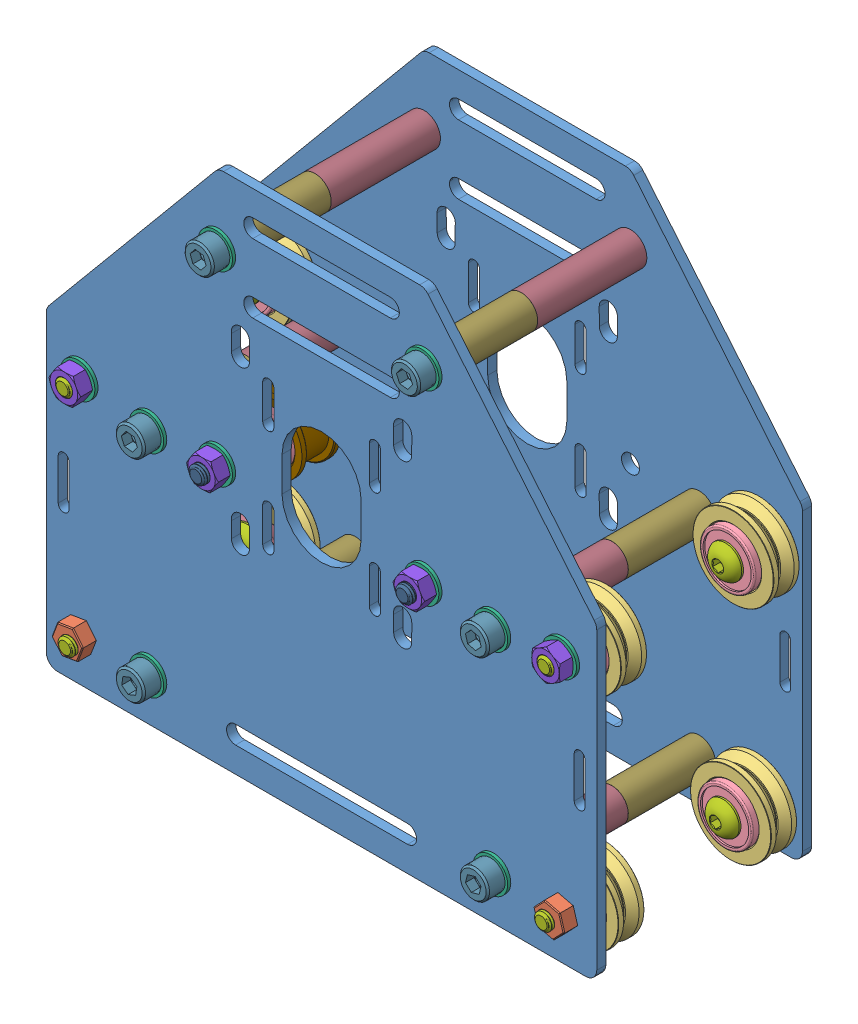
SolidWorks assembly ASM_S2_Yaxis_Plates, configuration Default. Lengths in mm.
Overall size (165.72 150 75.7).
154 component instances, 15 part files, 77 mates.
Components (placement in the parent):
- plate_assembly_stacked-2: plate_assembly_stacked [Default] at (181.8768 0 62.4637) x (-1 0 0) z (0 0 -1) size (164.61 150 32.91)
  - 26029-01-1: 26029-01 [Default] at origin size (160 150 2.66)
  - B18033-1: B18033 [Default] at (160.9384 20.9044 -3.9878) x (-0.352192 0.935928 0) z (0 0 1) size (9.18 7.95 5.26)
  - B18033-2: B18033 [Default] at (20.9384 20.9044 -3.9878) x (-0.283832 -0.958874 0) z (0 0 1) size (9.18 7.95 5.26)
  - 25203-02-1: 25203-02 [Default] at (20.9384 85.5044 9.0568) x (0.995036 -0.099517 0) z (-0.099517 -0.995036 0) size (23.5 11 23.5)
    - 25202-01-1: 25202-01 [Default] at origin size (23.5 7.5 23.5)
    - 25196-01-1: 25196-01 [Default] at (0 -3 0) x (0.224141 0 -0.974557) z (-0.974557 0 -0.224141) size (16 5 16)
    - 25201-01-1: 25201-01 [Default] at (0 -0.5 0) x (0.992075 0 -0.125646) z (0.125646 0 0.992075) size (10 1 10)
    - 25196-01-2: 25196-01 [Default] at (0 3 0) x (-0.996407 0 -0.084695) z (-0.084695 0 0.996407) size (16 5 16)
  - 25287-02-1: 25287-02 [Default] at (20.9384 85.5044 3.5568) size (10 10 0.9)
  - 91239A233-1: 91239A233 [Default] at (20.9384 85.5044 -5.4432) x (1 0 0) z (0 0 -1) size (9.5 9.5 22.91)
  - 25287-02-2: 25287-02 [Default] at (160.2015 20.6271 2.6568) x (-0.923728 -0.383049 0) z (0 0 -1) size (10 10 0.9)
  - 25284-02-1: 25284-02 [Default] at (20.9384 85.5044 -2.9) x (1 0 0) z (0 -1 0) size (8 4.29 9.24)
  - 25287-02-3: 25287-02 [Default] at (160.9384 85.5044 0) size (10 10 0.9)
  - 25287-02-4: 25287-02 [Default] at (160.9384 85.5044 3.5568) size (10 10 0.9)
  - 25287-02-5: 25287-02 [Default] at (21.6934 20.6809 2.6568) x (-0.923728 -0.383049 0) z (0 0 -1) size (10 10 0.9)
  - 25287-02-6: 25287-02 [Default] at (20.9384 85.5044 -0.9) x (1 0 0) z (0 0 -1) size (10 10 0.9)
  - 91239A233-2: 91239A233 [Default] at (21.6934 20.6809 -5.4432) x (1 0 0) z (0 0 -1) size (9.5 9.5 22.91)
  - 25203-02-2: 25203-02 [Default] at (21.6934 20.6809 9.0568) x (1 0 0) z (0 1 0) size (23.5 11 23.5)
    - 25202-01-1: 25202-01 [Default] at origin size (23.5 7.5 23.5)
    - 25196-01-1: 25196-01 [Default] at (0 -3 0) x (0.224141 0 -0.974557) z (-0.974557 0 -0.224141) size (16 5 16)
    - 25201-01-1: 25201-01 [Default] at (0 -0.5 0) x (0.992075 0 -0.125646) z (0.125646 0 0.992075) size (10 1 10)
    - 25196-01-2: 25196-01 [Default] at (0 3 0) x (-0.996407 0 -0.084695) z (-0.084695 0 0.996407) size (16 5 16)
  - 91239A233-3: 91239A233 [Default] at (160.2015 20.6271 -5.4432) x (1 0 0) z (0 0 -1) size (9.5 9.5 22.91)
  - 25203-02-3: 25203-02 [Default] at (160.2015 20.6271 9.0568) x (1 0 0) z (0 1 0) size (23.5 11 23.5)
    - 25202-01-1: 25202-01 [Default] at origin size (23.5 7.5 23.5)
    - 25196-01-1: 25196-01 [Default] at (0 -3 0) x (0.224141 0 -0.974557) z (-0.974557 0 -0.224141) size (16 5 16)
    - 25201-01-1: 25201-01 [Default] at (0 -0.5 0) x (0.992075 0 -0.125646) z (0.125646 0 0.992075) size (10 1 10)
    - 25196-01-2: 25196-01 [Default] at (0 3 0) x (-0.996407 0 -0.084695) z (-0.084695 0 0.996407) size (16 5 16)
  - 91239A233-4: 91239A233 [Default] at (160.9384 85.5044 -5.4432) x (1 0 0) z (0 0 -1) size (9.5 9.5 22.91)
  - 25203-02-4: 25203-02 [Default] at (160.9384 85.5044 9.0568) x (1 0 0) z (0 -1 0) size (23.5 11 23.5)
    - 25202-01-1: 25202-01 [Default] at origin size (23.5 7.5 23.5)
    - 25196-01-1: 25196-01 [Default] at (0 -3 0) x (0.224141 0 -0.974557) z (-0.974557 0 -0.224141) size (16 5 16)
    - 25201-01-1: 25201-01 [Default] at (0 -0.5 0) x (0.992075 0 -0.125646) z (0.125646 0 0.992075) size (10 1 10)
    - 25196-01-2: 25196-01 [Default] at (0 3 0) x (-0.996407 0 -0.084695) z (-0.084695 0 0.996407) size (16 5 16)
  - 25284-02-2: 25284-02 [Default] at (160.9384 85.5044 -2.9) x (0.037474 -0.999298 0) z (-0.999298 -0.037474 0) size (8 4.29 9.24)
  - 25197-02-1: 25197-02 [Default] at (128.9783 132.3034 54.0684) x (0 0 -1) z (-0.954972 -0.296697 0) size (12.6 21 21)
    - 25201-01-1: 25201-01 [Default] at (36.6716 43.7387 22.0081) x (0 1 0) z (0 0 1) size (10 1 10)
    - 25196-01-1: 25196-01 [Default] at (39.1716 43.7387 22.0081) x (0 1 0) z (0 0 1) size (16 5 16)
    - 25196-01-2: 25196-01 [Default] at (33.1716 43.7387 22.0081) x (0 1 0) z (0 0 1) size (16 5 16)
    - 25197-01-1: 25197-01 [Default] at (34.6716 43.7387 22.0081) size (11.2 21 21)
  - 25197-02-2: 25197-02 [Default] at (57.254 35.1797 54.0684) x (0 0 -1) z (0.92458 0.380987 0) size (12.6 21 21)
    - 25201-01-1: 25201-01 [Default] at (36.6716 43.7387 22.0081) x (0 1 0) z (0 0 1) size (10 1 10)
    - 25196-01-1: 25196-01 [Default] at (39.1716 43.7387 22.0081) x (0 1 0) z (0 0 1) size (16 5 16)
    - 25196-01-2: 25196-01 [Default] at (33.1716 43.7387 22.0081) x (0 1 0) z (0 0 1) size (16 5 16)
    - 25197-01-1: 25197-01 [Default] at (34.6716 43.7387 22.0081) size (11.2 21 21)
  - 25286-05-1: 25286-05 [Default] at (120.9384 84.0044 -6.6032) x (-0.651947 -0.758265 0) z (0 0 -1) size (9.5 9.5 32.91)
  - 25287-02-7: 25287-02 [Default] at (120.9384 84.0044 0) size (10 10 0.9)
  - 25284-02-3: 25284-02 [Default] at (120.9384 84.0044 -2.9) x (0.037474 -0.999298 0) z (-0.999298 -0.037474 0) size (8 4.29 9.24)
  - 25286-05-2: 25286-05 [Default] at (60.9384 84.0044 -6.6032) x (0.940642 0.3394 0) z (0 0 -1) size (9.5 9.5 32.91)
  - 25284-02-4: 25284-02 [Default] at (60.9384 84.0044 -2.9) x (-0.037474 0.999298 0) z (-0.999298 -0.037474 0) size (8 4.29 9.24)
  - 25287-02-8: 25287-02 [Default] at (60.9384 84.0044 0) x (-0.99589 0.090569 0) z (0 0 1) size (10 10 0.9)
  - 25312-14-1: 25312-14 [Default] at (60.9384 84.0044 4.4568) x (-0.162265 0.986747 0) z (0 0 1) size (9.53 9.53 7.94)
  - 25312-14-2: 25312-14 [Default] at (120.9384 84.0044 12.3968) x (0.519042 -0.854749 0) z (0 0 -1) size (9.53 9.53 7.94)
  - 25287-02-9: 25287-02 [Default] at (60.9384 84.0044 2.6568) x (0.999419 -0.034095 0) z (0 0 -1) size (10 10 0.9)
  - 25287-02-10: 25287-02 [Default] at (60.9384 84.0044 4.4568) x (0.999419 0.034095 0) z (0 0 1) size (10 10 0.9)
  - 25287-02-11: 25287-02 [Default] at (120.9384 84.0044 3.5568) x (0.999419 -0.034095 0) z (0 0 -1) size (10 10 0.9)
  - 25287-02-12: 25287-02 [Default] at (120.9384 84.0044 2.6568) x (0.999419 -0.034095 0) z (0 0 -1) size (10 10 0.9)
- plate_assembly_stacked-1: plate_assembly_stacked [No_Belt] at origin size (164.61 150 22.91)
  - 26029-01-1: 26029-01 [Default] at origin size (160 150 2.66)
  - B18033-1: B18033 [Default] at (160.9384 20.9044 -3.9878) x (-0.352192 0.935928 0) z (0 0 1) size (9.18 7.95 5.26)
  - B18033-2: B18033 [Default] at (20.9384 20.9044 -3.9878) x (-0.283832 -0.958874 0) z (0 0 1) size (9.18 7.95 5.26)
  - 25203-02-1: 25203-02 [Default] at (20.9384 85.5044 9.0568) x (0.995036 -0.099517 0) z (-0.099517 -0.995036 0) size (23.5 11 23.5)
    - 25202-01-1: 25202-01 [Default] at origin size (23.5 7.5 23.5)
    - 25196-01-1: 25196-01 [Default] at (0 -3 0) x (0.224141 0 -0.974557) z (-0.974557 0 -0.224141) size (16 5 16)
    - 25201-01-1: 25201-01 [Default] at (0 -0.5 0) x (0.992075 0 -0.125646) z (0.125646 0 0.992075) size (10 1 10)
    - 25196-01-2: 25196-01 [Default] at (0 3 0) x (-0.996407 0 -0.084695) z (-0.084695 0 0.996407) size (16 5 16)
  - 25287-02-1: 25287-02 [Default] at (20.9384 85.5044 3.5568) size (10 10 0.9)
  - 91239A233-1: 91239A233 [Default] at (20.9384 85.5044 -5.4432) x (1 0 0) z (0 0 -1) size (9.5 9.5 22.91)
  - 25287-02-2: 25287-02 [Default] at (160.2015 20.6271 2.6568) x (-0.923728 -0.383049 0) z (0 0 -1) size (10 10 0.9)
  - 25284-02-1: 25284-02 [Default] at (20.9384 85.5044 -2.9) x (1 0 0) z (0 -1 0) size (8 4.29 9.24)
  - 25287-02-3: 25287-02 [Default] at (160.9384 85.5044 0) size (10 10 0.9)
  - 25287-02-4: 25287-02 [Default] at (160.9384 85.5044 3.5568) size (10 10 0.9)
  - 25287-02-5: 25287-02 [Default] at (21.6934 20.6809 2.6568) x (-0.923728 -0.383049 0) z (0 0 -1) size (10 10 0.9)
  - 25287-02-6: 25287-02 [Default] at (20.9384 85.5044 -0.9) x (1 0 0) z (0 0 -1) size (10 10 0.9)
  - 91239A233-2: 91239A233 [Default] at (21.6934 20.6809 -5.4432) x (1 0 0) z (0 0 -1) size (9.5 9.5 22.91)
  - 25203-02-2: 25203-02 [Default] at (21.6934 20.6809 9.0568) x (1 0 0) z (0 1 0) size (23.5 11 23.5)
    - 25202-01-1: 25202-01 [Default] at origin size (23.5 7.5 23.5)
    - 25196-01-1: 25196-01 [Default] at (0 -3 0) x (0.224141 0 -0.974557) z (-0.974557 0 -0.224141) size (16 5 16)
    - 25201-01-1: 25201-01 [Default] at (0 -0.5 0) x (0.992075 0 -0.125646) z (0.125646 0 0.992075) size (10 1 10)
    - 25196-01-2: 25196-01 [Default] at (0 3 0) x (-0.996407 0 -0.084695) z (-0.084695 0 0.996407) size (16 5 16)
  - 91239A233-3: 91239A233 [Default] at (160.2015 20.6271 -5.4432) x (1 0 0) z (0 0 -1) size (9.5 9.5 22.91)
  - 25203-02-3: 25203-02 [Default] at (160.2015 20.6271 9.0568) x (1 0 0) z (0 1 0) size (23.5 11 23.5)
    - 25202-01-1: 25202-01 [Default] at origin size (23.5 7.5 23.5)
    - 25196-01-1: 25196-01 [Default] at (0 -3 0) x (0.224141 0 -0.974557) z (-0.974557 0 -0.224141) size (16 5 16)
    - 25201-01-1: 25201-01 [Default] at (0 -0.5 0) x (0.992075 0 -0.125646) z (0.125646 0 0.992075) size (10 1 10)
    - 25196-01-2: 25196-01 [Default] at (0 3 0) x (-0.996407 0 -0.084695) z (-0.084695 0 0.996407) size (16 5 16)
  - 91239A233-4: 91239A233 [Default] at (160.9384 85.5044 -5.4432) x (1 0 0) z (0 0 -1) size (9.5 9.5 22.91)
  - 25203-02-4: 25203-02 [Default] at (160.9384 85.5044 9.0568) x (1 0 0) z (0 -1 0) size (23.5 11 23.5)
    - 25202-01-1: 25202-01 [Default] at origin size (23.5 7.5 23.5)
    - 25196-01-1: 25196-01 [Default] at (0 -3 0) x (0.224141 0 -0.974557) z (-0.974557 0 -0.224141) size (16 5 16)
    - 25201-01-1: 25201-01 [Default] at (0 -0.5 0) x (0.992075 0 -0.125646) z (0.125646 0 0.992075) size (10 1 10)
    - 25196-01-2: 25196-01 [Default] at (0 3 0) x (-0.996407 0 -0.084695) z (-0.084695 0 0.996407) size (16 5 16)
  - 25284-02-2: 25284-02 [Default] at (160.9384 85.5044 -2.9) x (0.037474 -0.999298 0) z (-0.999298 -0.037474 0) size (8 4.29 9.24)
  - 25197-02-1: 25197-02 [Default] at (128.9783 132.3034 54.0684) x (0 0 -1) z (-0.954972 -0.296697 0) size (12.6 21 21) (suppressed, hidden)
    - 25201-01-1: 25201-01 [Default] at (36.6716 43.7387 22.0081) x (0 1 0) z (0 0 1) size (10 1 10)
    - 25196-01-1: 25196-01 [Default] at (39.1716 43.7387 22.0081) x (0 1 0) z (0 0 1) size (16 5 16)
    - 25196-01-2: 25196-01 [Default] at (33.1716 43.7387 22.0081) x (0 1 0) z (0 0 1) size (16 5 16)
    - 25197-01-1: 25197-01 [Default] at (34.6716 43.7387 22.0081) size (11.2 21 21)
  - 25197-02-2: 25197-02 [Default] at (57.254 35.1797 54.0684) x (0 0 -1) z (0.92458 0.380987 0) size (12.6 21 21) (suppressed, hidden)
    - 25201-01-1: 25201-01 [Default] at (36.6716 43.7387 22.0081) x (0 1 0) z (0 0 1) size (10 1 10)
    - 25196-01-1: 25196-01 [Default] at (39.1716 43.7387 22.0081) x (0 1 0) z (0 0 1) size (16 5 16)
    - 25196-01-2: 25196-01 [Default] at (33.1716 43.7387 22.0081) x (0 1 0) z (0 0 1) size (16 5 16)
    - 25197-01-1: 25197-01 [Default] at (34.6716 43.7387 22.0081) size (11.2 21 21)
  - 25286-05-1: 25286-05 [Default] at (120.9384 84.0044 -6.6032) x (-0.651947 -0.758265 0) z (0 0 -1) size (9.5 9.5 32.91) (suppressed, hidden)
  - 25287-02-7: 25287-02 [Default] at (120.9384 84.0044 0) size (10 10 0.9) (suppressed, hidden)
  - 25284-02-3: 25284-02 [Default] at (120.9384 84.0044 -2.9) x (0.037474 -0.999298 0) z (-0.999298 -0.037474 0) size (8 4.29 9.24) (suppressed, hidden)
  - 25286-05-2: 25286-05 [Default] at (60.9384 84.0044 -6.6032) x (0.940642 0.3394 0) z (0 0 -1) size (9.5 9.5 32.91) (suppressed, hidden)
  - 25284-02-4: 25284-02 [Default] at (60.9384 84.0044 -2.9) x (-0.037474 0.999298 0) z (-0.999298 -0.037474 0) size (8 4.29 9.24) (suppressed, hidden)
  - 25287-02-8: 25287-02 [Default] at (60.9384 84.0044 0) x (-0.99589 0.090569 0) z (0 0 1) size (10 10 0.9) (suppressed, hidden)
  - 25312-14-1: 25312-14 [Default] at (60.9384 84.0044 4.4568) x (-0.162265 0.986747 0) z (0 0 1) size (9.53 9.53 7.94) (suppressed, hidden)
  - 25312-14-2: 25312-14 [Default] at (120.9384 84.0044 12.3968) x (0.519042 -0.854749 0) z (0 0 -1) size (9.53 9.53 7.94) (suppressed, hidden)
  - 25287-02-9: 25287-02 [Default] at (60.9384 84.0044 2.6568) x (0.999419 -0.034095 0) z (0 0 -1) size (10 10 0.9) (suppressed, hidden)
  - 25287-02-10: 25287-02 [Default] at (60.9384 84.0044 4.4568) x (0.999419 0.034095 0) z (0 0 1) size (10 10 0.9) (suppressed, hidden)
  - 25287-02-11: 25287-02 [Default] at (120.9384 84.0044 3.5568) x (0.999419 -0.034095 0) z (0 0 -1) size (10 10 0.9) (suppressed, hidden)
  - 25287-02-12: 25287-02 [Default] at (120.9384 84.0044 2.6568) x (0.999419 -0.034095 0) z (0 0 -1) size (10 10 0.9) (suppressed, hidden)
- AS38-12-64-1: AS38-12-64 [Default] at (120.9384 138.2044 59.8068) x (1 0 0) z (0 0 -1) size (9.53 9.53 25.4)
- 91290A272-1: 91290A272 [Default] at (152.9795 421.0336 165.2742) x (-0.956811 0.027475 0.289409) z (-0.289409 0.004064 -0.957197) (suppressed, hidden)
- 25284-02-7: 25284-02 [Default] at (120.9384 138.2044 -2.9) x (-0.5 0.866025 0) z (0.866025 0.5 0) size (8 4.29 9.24)
- 25287-02-18: 25287-02 [Default] at (120.9384 138.2044 63.3637) x (0.999606 -0.028076 0) z (0 0 1) size (10 10 0.9)
- 25287-02-19: 25287-02 [Default] at (120.9384 138.2044 -0.9) x (-0.999993 0.003617 0) z (0 0 -1) size (10 10 0.9)
- AS38-12-80-1: AS38-12-80 [Default] at (120.9384 138.2044 2.6568) x (-0.089218 0.996012 0) z (0 0 1) size (9.53 9.53 31.75)
- 25284-02-10: 25284-02 [Default] at (140.9384 82.4044 -2.9) x (0.999993 -0.003617 0) z (-0.003617 -0.999993 0) size (8 4.29 9.24)
- 25287-02-25: 25287-02 [Default] at (140.9384 82.4044 -0.9) x (-0.301994 -0.95331 0) z (0 0 -1) size (10 10 0.9)
- 25284-02-11: 25284-02 [Default] at (140.9384 20.9044 -2.9) x (-0.5 0.866025 0) z (0.866025 0.5 0) size (8 4.29 9.24)
- 25287-02-26: 25287-02 [Default] at (140.9384 20.9044 -0.9) x (-0.999993 0.003617 0) z (0 0 -1) size (10 10 0.9)
- 25284-02-12: 25284-02 [Default] at (40.9384 20.9044 -2.9) x (0 1 0) z (1 0 0) size (8 4.29 9.24)
- 25287-02-27: 25287-02 [Default] at (40.9384 20.9044 -0.9) x (-0.999993 0.003617 0) z (0 0 -1) size (10 10 0.9)
- 25284-02-13: 25284-02 [Default] at (40.9384 82.4044 -2.9) x (0.999993 -0.003617 0) z (-0.003617 -0.999993 0) size (8 4.29 9.24)
- 25287-02-28: 25287-02 [Default] at (40.9384 82.4044 -0.9) x (-0.999993 0.003617 0) z (0 0 -1) size (10 10 0.9)
- 25287-02-29: 25287-02 [Default] at (140.9384 82.4044 63.3637) x (0.999606 -0.028076 0) z (0 0 1) size (10 10 0.9)
- 25287-02-30: 25287-02 [Default] at (140.9384 20.9044 63.3637) x (0.999606 -0.028076 0) z (0 0 1) size (10 10 0.9)
- 25287-02-31: 25287-02 [Default] at (40.9384 20.9044 63.3637) x (0.999606 -0.028076 0) z (0 0 1) size (10 10 0.9)
- 25287-02-32: 25287-02 [Default] at (40.9384 82.4044 63.3637) x (0.999606 -0.028076 0) z (0 0 1) size (10 10 0.9)
- AS38-12-64-2: AS38-12-64 [Default] at (140.9384 82.4044 2.6568) x (-0.981238 0.192798 0) z (0 0 1) size (9.53 9.53 25.4)
- AS38-12-80-2: AS38-12-80 [Default] at (140.9384 82.4044 59.8068) x (-0.999606 0.028076 0) z (0 0 -1) size (9.53 9.53 31.75)
- AS38-12-64-3: AS38-12-64 [Default] at (140.9384 20.9044 2.6568) x (-0.999606 0.028076 0) z (0 0 1) size (9.53 9.53 25.4)
- AS38-12-80-3: AS38-12-80 [Default] at (140.9384 20.9044 59.8068) x (-0.340287 0.940322 0) z (0 0 -1) size (9.53 9.53 31.75)
- AS38-12-64-4: AS38-12-64 [Default] at (40.9384 20.9044 2.6568) x (-0.999606 0.028076 0) z (0 0 1) size (9.53 9.53 25.4)
- AS38-12-80-4: AS38-12-80 [Default] at (40.9384 20.9044 59.8068) x (0.154744 0.987955 0) z (0 0 -1) size (9.53 9.53 31.75)
- AS38-12-64-5: AS38-12-64 [Default] at (40.9384 82.4044 59.8068) x (0.848591 -0.52905 0) z (0 0 -1) size (9.53 9.53 25.4)
- AS38-12-80-5: AS38-12-80 [Default] at (40.9384 82.4044 2.6568) size (9.53 9.53 31.75)
- 91290A272-6: 91290A272 [Default] at (88.3739 418.8513 182.2519) x (-0.956811 0.027475 0.289409) z (-0.289409 0.004064 -0.957197) (suppressed, hidden)
- 25287-02-33: 25287-02 [Default] at (60.9384 138.2044 63.3637) x (0.996766 -0.080363 0) z (0 0 1) size (10 10 0.9)
- AS38-12-64-6: AS38-12-64 [Default] at (60.9384 138.2044 59.8068) x (0.961654 -0.274264 0) z (0 0 -1) size (9.53 9.53 25.4)
- AS38-12-80-6: AS38-12-80 [Default] at (60.9384 138.2044 2.6568) x (0.870274 0.492568 0) z (0 0 1) size (9.53 9.53 31.75)
- 25284-02-14: 25284-02 [Default] at (60.9384 138.2044 -2.9) x (-0.282733 0.959199 0) z (0.959199 0.282733 0) size (8 4.29 9.24)
- 25287-02-34: 25287-02 [Default] at (60.9384 138.2044 -0.9) x (-0.998433 0.055958 0) z (0 0 -1) size (10 10 0.9)
- socket head cap screw_am-1: socket head cap screw_am [B18.3.1M - 5 x 0.8 x 70 Hex SHCS -- 22CHX] at (60.9384 138.2044 68.3637) x (0 0 -1) z (0.770803 -0.637073 0) size (75 8.5 8.5)
- socket head cap screw_am-2: socket head cap screw_am [B18.3.1M - 5 x 0.8 x 70 Hex SHCS -- 22CHX] at (120.9384 138.2044 68.3637) x (0 0 -1) z (0.803095 -0.595852 0) size (75 8.5 8.5)
- socket head cap screw_am-3: socket head cap screw_am [B18.3.1M - 5 x 0.8 x 70 Hex SHCS -- 22CHX] at (140.9384 20.9044 68.3637) x (0 0 -1) z (0.695931 0.718108 0) size (75 8.5 8.5)
- socket head cap screw_am-4: socket head cap screw_am [B18.3.1M - 5 x 0.8 x 70 Hex SHCS -- 22CHX] at (140.9384 82.4044 68.3637) x (0 0 -1) z (-0.233792 -0.972287 0) size (75 8.5 8.5)
- socket head cap screw_am-5: socket head cap screw_am [B18.3.1M - 5 x 0.8 x 70 Hex SHCS -- 22CHX] at (40.9384 20.9044 68.3637) x (0 0 -1) z (-0.61871 -0.785619 0) size (75 8.5 8.5)
- socket head cap screw_am-7: socket head cap screw_am [B18.3.1M - 5 x 0.8 x 70 Hex SHCS -- 22CHX] at (40.9384 82.4044 68.3637) x (0 0 -1) z (-0.117912 -0.993024 0) size (75 8.5 8.5)
Mates (geometry in assembly coordinates):
- Coincident1: coordinate: point of plate_assembly_stacked-1/26029-01-1
- Concentric1: concentric anti-aligned: cylinder of plate_assembly_stacked-1/26029-01-1 through (60.9384 138.2044 2.6568) axis (0 0 -1) radius 2.625; cylinder of plate_assembly_stacked-2/26029-01-1 through (60.9384 138.2044 59.8068) axis (0 0 1) radius 2.625
- Concentric2: concentric anti-aligned: cylinder of plate_assembly_stacked-1/26029-01-1 through (120.9384 138.2044 2.6568) axis (0 0 -1) radius 2.625; cylinder of plate_assembly_stacked-2/26029-01-1 through (120.9384 138.2044 59.8068) axis (0 0 1) radius 2.625
- Concentric31: concentric anti-aligned: cylinder of AS38-12-64-6 through (60.9384 138.2044 59.8068) axis (0 0 -1) radius 2.78; cylinder of socket head cap screw_am-1 through (60.9384 138.2044 100.1137) axis (0 0 1) radius 4.25
- Concentric4: concentric aligned: cylinder of 25287-02-33 through (60.9384 138.2044 62.4637) axis (0 0 1) radius 2.65; cylinder of socket head cap screw_am-1 through (60.9384 138.2044 100.1137) axis (0 0 1) radius 2.5
- Concentric5: concentric aligned: cylinder of AS38-12-80-6 through (60.9384 138.2044 2.6568) axis (0 0 1) radius 2.7813; cylinder of socket head cap screw_am-1 through (60.9384 138.2044 100.1137) axis (0 0 1) radius 2.5
- Concentric6: concentric anti-aligned: cylinder of 25287-02-34 through (60.9384 138.2044 0) axis (0 0 -1) radius 2.65; cylinder of socket head cap screw_am-1 through (60.9384 138.2044 100.1137) axis (0 0 1) radius 2.5
- Concentric7: concentric aligned: circle of 25284-02-14; cylinder of socket head cap screw_am-1 through (60.9384 138.2044 100.1137) axis (0 0 1) radius 2.5
- Coincident4: coincident anti-aligned: plane of 25284-02-14 through (56.5081 136.8985 -0.9) normal (0 0 1); plane of 25287-02-34 through (60.9384 138.2044 -0.9) normal (0 0 -1)
- Coincident5: coincident anti-aligned: plane of AS38-12-64-6 through (60.9384 138.2044 34.4068) normal (0 0 -1); plane of AS38-12-80-6 through (60.9384 138.2044 34.4068) normal (0 0 1)
- Coincident6: coincident anti-aligned: plane of 25287-02-33 through (60.9384 138.2044 63.3637) normal (0 0 1); plane of socket head cap screw_am-1 through (63.646 141.4803 63.3637) normal (0 0 -1)
- Concentric8: concentric aligned: cylinder of 25287-02-18 through (120.9384 138.2044 62.4637) axis (0 0 1) radius 2.65; cylinder of socket head cap screw_am-2 through (120.9384 138.2044 100.1137) axis (0 0 1) radius 2.5
- Concentric9: concentric anti-aligned: cylinder of AS38-12-64-1 through (120.9384 138.2044 59.8068) axis (0 0 -1) radius 2.78; cylinder of socket head cap screw_am-2 through (120.9384 138.2044 100.1137) axis (0 0 1) radius 2.5
- Concentric10: concentric aligned: cylinder of AS38-12-80-1 through (120.9384 138.2044 2.6568) axis (0 0 1) radius 2.7813; cylinder of socket head cap screw_am-2 through (120.9384 138.2044 100.1137) axis (0 0 1) radius 2.5
- Concentric11: concentric anti-aligned: cylinder of 25287-02-19 through (120.9384 138.2044 0) axis (0 0 -1) radius 2.65; cylinder of socket head cap screw_am-2 through (120.9384 138.2044 100.1137) axis (0 0 1) radius 2.5
- Concentric12: concentric aligned: circle of 25284-02-7; cylinder of socket head cap screw_am-2 through (120.9384 138.2044 100.1137) axis (0 0 1) radius 2.5
- Coincident7: coincident anti-aligned: plane of 25284-02-7 through (116.9384 135.895 -0.9) normal (0 0 1); plane of 25287-02-19 through (120.9384 138.2044 -0.9) normal (0 0 -1)
- Coincident8: coincident anti-aligned: plane of AS38-12-64-1 through (120.9384 138.2044 34.4068) normal (0 0 -1); plane of AS38-12-80-1 through (120.9384 138.2044 34.4068) normal (0 0 1)
- Coincident9: coincident anti-aligned: plane of 25287-02-18 through (120.9384 138.2044 63.3637) normal (0 0 1); plane of socket head cap screw_am-2 through (123.4708 141.6176 63.3637) normal (0 0 -1)
- Concentric14: concentric aligned: cylinder of plate_assembly_stacked-2/26029-01-1 through (120.9384 138.2044 59.8068) axis (0 0 1) radius 2.625; cylinder of socket head cap screw_am-2 through (120.9384 138.2044 100.1137) axis (0 0 1) radius 2.5
- Concentric15: concentric aligned: cylinder of plate_assembly_stacked-2/26029-01-1 through (60.9384 138.2044 59.8068) axis (0 0 1) radius 2.625; cylinder of socket head cap screw_am-1 through (60.9384 138.2044 100.1137) axis (0 0 1) radius 2.5
- Coincident10: coincident anti-aligned: plane of AS38-12-64-6 through (60.9384 138.2044 59.8068) normal (0 0 1); plane of plate_assembly_stacked-2/26029-01-1 through (90.9384 72.6493 59.8068) normal (0 0 -1)
- Coincident11: coincident anti-aligned: plane of AS38-12-64-1 through (120.9384 138.2044 59.8068) normal (0 0 1); plane of plate_assembly_stacked-2/26029-01-1 through (90.9384 72.6493 59.8068) normal (0 0 -1)
- Coincident12: coincident anti-aligned: plane of AS38-12-80-6 through (60.9384 138.2044 2.6568) normal (0 0 -1); plane of plate_assembly_stacked-1/26029-01-1 through (90.9384 72.6493 2.6568) normal (0 0 1)
- Coincident13: coincident anti-aligned: plane of AS38-12-80-1 through (120.9384 138.2044 2.6568) normal (0 0 -1); plane of plate_assembly_stacked-1/26029-01-1 through (90.9384 72.6493 2.6568) normal (0 0 1)
- Coincident14: coincident anti-aligned: plane of 25287-02-19 through (120.9384 138.2044 0) normal (0 0 1); plane of plate_assembly_stacked-1/26029-01-1 through (90.9384 72.6493 0) normal (0 0 -1)
- Coincident15: coincident anti-aligned: plane of 25287-02-34 through (60.9384 138.2044 0) normal (0 0 1); plane of plate_assembly_stacked-1/26029-01-1 through (90.9384 72.6493 0) normal (0 0 -1)
- Coincident16: coincident anti-aligned: plane of 25287-02-18 through (120.9384 138.2044 62.4637) normal (0 0 -1); plane of plate_assembly_stacked-2/26029-01-1 through (90.9384 72.6493 62.4637) normal (0 0 1)
- Coincident17: coincident anti-aligned: plane of 25287-02-33 through (60.9384 138.2044 62.4637) normal (0 0 -1); plane of plate_assembly_stacked-2/26029-01-1 through (90.9384 72.6493 62.4637) normal (0 0 1)
- Concentric16: concentric aligned: cylinder of 25287-02-32 through (40.9384 82.4044 62.4637) axis (0 0 1) radius 5; cylinder of socket head cap screw_am-7 through (40.9384 82.4044 100.1137) axis (0 0 1) radius 2.5
- Concentric17: concentric aligned: cylinder of 25287-02-31 through (40.9384 20.9044 62.4637) axis (0 0 1) radius 5; cylinder of socket head cap screw_am-5 through (40.9384 20.9044 100.1137) axis (0 0 1) radius 2.5
- Concentric18: concentric aligned: cylinder of 25287-02-30 through (140.9384 20.9044 62.4637) axis (0 0 1) radius 5; cylinder of socket head cap screw_am-3 through (140.9384 20.9044 100.1137) axis (0 0 1) radius 2.5
- Concentric19: concentric aligned: cylinder of 25287-02-29 through (140.9384 82.4044 62.4637) axis (0 0 1) radius 5; cylinder of socket head cap screw_am-4 through (140.9384 82.4044 100.1137) axis (0 0 1) radius 2.5
- Concentric20: concentric anti-aligned: cylinder of AS38-12-80-2 through (140.9384 82.4044 59.8068) axis (0 0 -1) radius 2.7813; cylinder of socket head cap screw_am-4 through (140.9384 82.4044 100.1137) axis (0 0 1) radius 2.5
- Concentric21: concentric aligned: cylinder of AS38-12-64-2 through (140.9384 82.4044 2.6568) axis (0 0 1) radius 2.78; cylinder of socket head cap screw_am-4 through (140.9384 82.4044 100.1137) axis (0 0 1) radius 2.5
- Concentric22: concentric anti-aligned: cylinder of 25287-02-25 through (140.9384 82.4044 0) axis (0 0 -1) radius 2.65; cylinder of socket head cap screw_am-4 through (140.9384 82.4044 100.1137) axis (0 0 1) radius 2.5
- Concentric23: concentric aligned: circle of 25284-02-10; cylinder of socket head cap screw_am-4 through (140.9384 82.4044 100.1137) axis (0 0 1) radius 2.5
- Concentric24: concentric anti-aligned: cylinder of AS38-12-64-5 through (40.9384 82.4044 59.8068) axis (0 0 -1) radius 2.78; cylinder of socket head cap screw_am-7 through (40.9384 82.4044 100.1137) axis (0 0 1) radius 2.5
- Concentric25: concentric aligned: cylinder of AS38-12-80-5 through (40.9384 82.4044 2.6568) axis (0 0 1) radius 2.7813; cylinder of socket head cap screw_am-7 through (40.9384 82.4044 100.1137) axis (0 0 1) radius 2.5
- Concentric26: concentric anti-aligned: cylinder of 25287-02-28 through (40.9384 82.4044 0) axis (0 0 -1) radius 5; cylinder of socket head cap screw_am-7 through (40.9384 82.4044 100.1137) axis (0 0 1) radius 2.5
- Concentric27: concentric aligned: circle of 25284-02-13; cylinder of socket head cap screw_am-7 through (40.9384 82.4044 100.1137) axis (0 0 1) radius 2.5
- Coincident18: coincident anti-aligned: plane of 25284-02-13 through (40.9551 87.0232 -0.9) normal (0 0 1); plane of 25287-02-28 through (40.9384 82.4044 -0.9) normal (0 0 -1)
- Coincident19: coincident anti-aligned: plane of AS38-12-64-5 through (40.9384 82.4044 34.4068) normal (0 0 -1); plane of AS38-12-80-5 through (40.9384 82.4044 34.4068) normal (0 0 1)
- Coincident20: coincident anti-aligned: plane of 25287-02-32 through (40.9384 82.4044 63.3637) normal (0 0 1); plane of socket head cap screw_am-7 through (45.1588 81.9033 63.3637) normal (0 0 -1)
- Coincident21: coincident anti-aligned: plane of 25287-02-29 through (140.9384 82.4044 63.3637) normal (0 0 1); plane of socket head cap screw_am-4 through (145.0706 81.4108 63.3637) normal (0 0 -1)
- Coincident22: coincident anti-aligned: plane of AS38-12-64-2 through (140.9384 82.4044 28.0568) normal (0 0 1); plane of AS38-12-80-2 through (140.9384 82.4044 28.0568) normal (0 0 -1)
- Coincident23: coincident anti-aligned: plane of 25284-02-10 through (140.9551 87.0232 -0.9) normal (0 0 1); plane of 25287-02-25 through (140.9384 82.4044 -0.9) normal (0 0 -1)
- Concentric28: concentric anti-aligned: cylinder of AS38-12-80-3 through (140.9384 20.9044 59.8068) axis (0 0 -1) radius 2.7813; cylinder of socket head cap screw_am-3 through (140.9384 20.9044 100.1137) axis (0 0 1) radius 2.5
- Concentric29: concentric aligned: cylinder of AS38-12-64-3 through (140.9384 20.9044 2.6568) axis (0 0 1) radius 2.78; cylinder of socket head cap screw_am-3 through (140.9384 20.9044 100.1137) axis (0 0 1) radius 2.5
- Concentric30: concentric anti-aligned: cylinder of 25287-02-26 through (140.9384 20.9044 0) axis (0 0 -1) radius 2.65; cylinder of socket head cap screw_am-3 through (140.9384 20.9044 100.1137) axis (0 0 1) radius 2.5
- Concentric31: concentric aligned: circle of 25284-02-11; cylinder of socket head cap screw_am-3 through (140.9384 20.9044 100.1137) axis (0 0 1) radius 2.5
- Coincident24: coincident anti-aligned: plane of 25284-02-11 through (136.9384 18.595 -0.9) normal (0 0 1); plane of 25287-02-26 through (140.9384 20.9044 -0.9) normal (0 0 -1)
- Coincident25: coincident anti-aligned: plane of AS38-12-64-3 through (140.9384 20.9044 28.0568) normal (0 0 1); plane of AS38-12-80-3 through (140.9384 20.9044 28.0568) normal (0 0 -1)
- Coincident26: coincident anti-aligned: plane of 25287-02-30 through (140.9384 20.9044 63.3637) normal (0 0 1); plane of socket head cap screw_am-3 through (137.8864 23.8621 63.3637) normal (0 0 -1)
- Coincident27: coincident anti-aligned: plane of 25287-02-31 through (40.9384 20.9044 63.3637) normal (0 0 1); plane of socket head cap screw_am-5 through (44.2773 18.2749 63.3637) normal (0 0 -1)
- Concentric32: concentric anti-aligned: cylinder of AS38-12-80-4 through (40.9384 20.9044 59.8068) axis (0 0 -1) radius 2.7813; cylinder of socket head cap screw_am-5 through (40.9384 20.9044 100.1137) axis (0 0 1) radius 2.5
- Concentric33: concentric aligned: cylinder of AS38-12-64-4 through (40.9384 20.9044 2.6568) axis (0 0 1) radius 2.78; cylinder of socket head cap screw_am-5 through (40.9384 20.9044 100.1137) axis (0 0 1) radius 2.5
- Concentric34: concentric anti-aligned: cylinder of 25287-02-27 through (40.9384 20.9044 0) axis (0 0 -1) radius 2.65; cylinder of socket head cap screw_am-5 through (40.9384 20.9044 100.1137) axis (0 0 1) radius 2.5
- Concentric35: concentric aligned: circle of 25284-02-12; cylinder of socket head cap screw_am-5 through (40.9384 20.9044 100.1137) axis (0 0 1) radius 2.5
- Coincident28: coincident anti-aligned: plane of 25284-02-12 through (36.3196 20.9044 -0.9) normal (0 0 1); plane of 25287-02-27 through (40.9384 20.9044 -0.9) normal (0 0 -1)
- Coincident29: coincident anti-aligned: plane of AS38-12-64-4 through (40.9384 20.9044 28.0568) normal (0 0 1); plane of AS38-12-80-4 through (40.9384 20.9044 28.0568) normal (0 0 -1)
- Concentric36: concentric anti-aligned: cylinder of plate_assembly_stacked-2/26029-01-1 through (40.9384 20.9044 62.4637) axis (0 0 -1) radius 2.625; cylinder of socket head cap screw_am-5 through (40.9384 20.9044 100.1137) axis (0 0 1) radius 2.5
- Concentric37: concentric anti-aligned: cylinder of plate_assembly_stacked-2/26029-01-1 through (40.9384 82.4044 62.4637) axis (0 0 -1) radius 2.625; cylinder of socket head cap screw_am-7 through (40.9384 82.4044 100.1137) axis (0 0 1) radius 2.5
- Concentric38: concentric anti-aligned: cylinder of plate_assembly_stacked-2/26029-01-1 through (140.9384 20.9044 62.4637) axis (0 0 -1) radius 2.625; cylinder of socket head cap screw_am-3 through (140.9384 20.9044 100.1137) axis (0 0 1) radius 2.5
- Concentric39: concentric anti-aligned: cylinder of plate_assembly_stacked-2/26029-01-1 through (140.9384 82.4044 62.4637) axis (0 0 -1) radius 2.625; cylinder of socket head cap screw_am-4 through (140.9384 82.4044 100.1137) axis (0 0 1) radius 2.5
- Coincident30: coincident anti-aligned: plane of AS38-12-64-5 through (40.9384 82.4044 59.8068) normal (0 0 1); plane of plate_assembly_stacked-2/26029-01-1 through (90.9384 72.6493 59.8068) normal (0 0 -1)
- Coincident31: coincident anti-aligned: plane of AS38-12-80-4 through (40.9384 20.9044 59.8068) normal (0 0 1); plane of plate_assembly_stacked-2/26029-01-1 through (90.9384 72.6493 59.8068) normal (0 0 -1)
- Coincident32: coincident anti-aligned: plane of AS38-12-80-2 through (140.9384 82.4044 59.8068) normal (0 0 1); plane of plate_assembly_stacked-2/26029-01-1 through (90.9384 72.6493 59.8068) normal (0 0 -1)
- Coincident33: coincident anti-aligned: plane of AS38-12-80-3 through (140.9384 20.9044 59.8068) normal (0 0 1); plane of plate_assembly_stacked-2/26029-01-1 through (90.9384 72.6493 59.8068) normal (0 0 -1)
- Coincident34: coincident anti-aligned: plane of 25287-02-28 through (40.9384 82.4044 0) normal (0 0 1); plane of plate_assembly_stacked-1/26029-01-1 through (90.9384 72.6493 0) normal (0 0 -1)
- Coincident35: coincident anti-aligned: plane of 25287-02-27 through (40.9384 20.9044 0) normal (0 0 1); plane of plate_assembly_stacked-1/26029-01-1 through (90.9384 72.6493 0) normal (0 0 -1)
- Coincident36: coincident anti-aligned: plane of 25287-02-25 through (140.9384 82.4044 0) normal (0 0 1); plane of plate_assembly_stacked-1/26029-01-1 through (90.9384 72.6493 0) normal (0 0 -1)
- Coincident37: coincident anti-aligned: plane of 25287-02-26 through (140.9384 20.9044 0) normal (0 0 1); plane of plate_assembly_stacked-1/26029-01-1 through (90.9384 72.6493 0) normal (0 0 -1)
- Coincident38: coincident anti-aligned: plane of 25287-02-30 through (140.9384 20.9044 62.4637) normal (0 0 -1); plane of plate_assembly_stacked-2/26029-01-1 through (90.9384 72.6493 62.4637) normal (0 0 1)
- Coincident39: coincident anti-aligned: plane of 25287-02-29 through (140.9384 82.4044 62.4637) normal (0 0 -1); plane of plate_assembly_stacked-2/26029-01-1 through (90.9384 72.6493 62.4637) normal (0 0 1)
- Coincident40: coincident anti-aligned: plane of 25287-02-32 through (40.9384 82.4044 62.4637) normal (0 0 -1); plane of plate_assembly_stacked-2/26029-01-1 through (90.9384 72.6493 62.4637) normal (0 0 1)
- Coincident41: coincident anti-aligned: plane of 25287-02-31 through (40.9384 20.9044 62.4637) normal (0 0 -1); plane of plate_assembly_stacked-2/26029-01-1 through (90.9384 72.6493 62.4637) normal (0 0 1)
